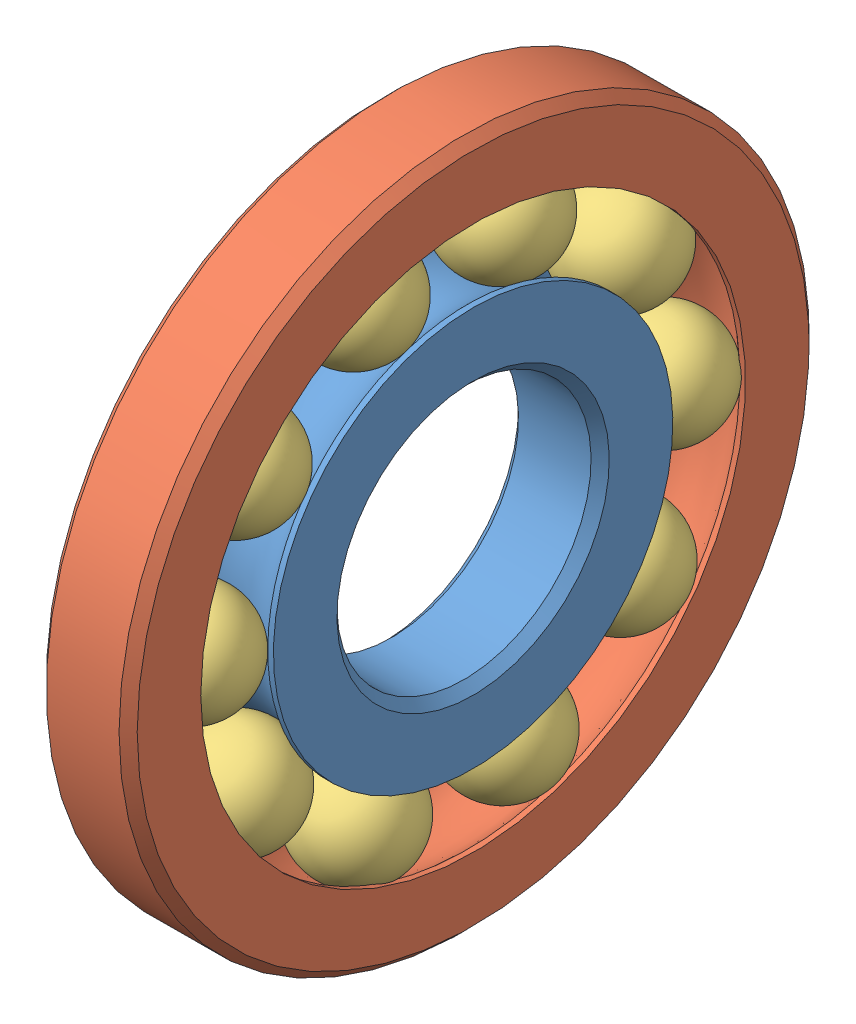
SolidWorks assembly BEARING, configuration Default. Lengths in mm.
Overall size (6 38 38).
12 component instances, 3 part files, 3 mates.
Components (placement in the parent):
- Bearing inner ring-1: Bearing inner ring [Default] at (42.2153 13.7206 -61.314) x (1 0 0) z (0 -0.985071 -0.172151) size (5 22 22)
- bearing outer ring2-1: bearing outer ring2 [Default] at (42.2153 13.7206 -61.314) size (5 38 38)
- ball-1: ball [Default] at (42.2153 26.1529 -65.2814) size (6 6 6)
- ball-2: ball [Default] at (42.2153 21.4466 -71.8312) x (1 0 0) z (0 0.587785 0.809017) size (6 6 6)
- ball-3: ball [Default] at (42.2153 13.7892 -74.3639) x (1 0 0) z (0 0.951057 0.309017) size (6 6 6)
- ball-4: ball [Default] at (42.2153 6.1056 -71.9119) x (1 0 0) z (0 0.951057 -0.309017) size (6 6 6)
- ball-5: ball [Default] at (42.2153 1.3307 -65.4119) x (1 0 0) z (0 0.587785 -0.809017) size (6 6 6)
- ball-6: ball [Default] at (42.2153 1.2883 -57.3467) x (1 0 0) z (0 0 -1) size (6 6 6)
- ball-7: ball [Default] at (42.2153 5.9946 -50.7968) x (1 0 0) z (0 -0.587785 -0.809017) size (6 6 6)
- ball-8: ball [Default] at (42.2153 13.652 -48.2642) x (1 0 0) z (0 -0.951057 -0.309017) size (6 6 6)
- ball-9: ball [Default] at (42.2153 21.3356 -50.7162) x (1 0 0) z (0 -0.951057 0.309017) size (6 6 6)
- ball-10: ball [Default] at (42.2153 26.1105 -57.2162) x (1 0 0) z (0 -0.587785 0.809017) size (6 6 6)
Mates (geometry in assembly coordinates):
- Concentric1: concentric aligned: circle of Bearing inner ring-1; circle of bearing outer ring2-1
- Width1: width anti-aligned: plane of Bearing inner ring-1 through (44.7153 12.5155 -54.4185) normal (1 0 0); plane of Bearing inner ring-1 through (39.7153 12.5155 -54.4185) normal (-1 0 0); plane of bearing outer ring2-1 through (39.7153 13.7206 -61.314) normal (-1 0 0); plane of bearing outer ring2-1 through (44.7153 13.7206 -61.314) normal (1 0 0)
- Tangent1: tangent: torus of Bearing inner ring-1; sphere of ball-1
